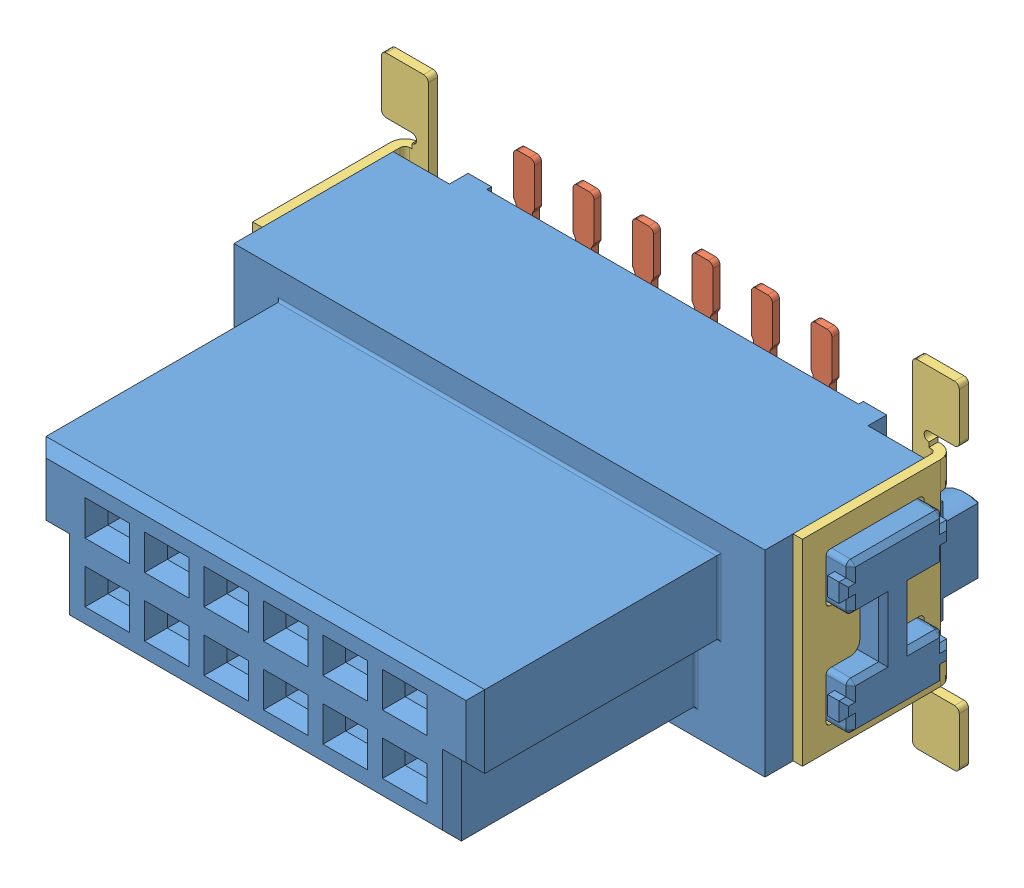
SolidWorks assembly m55-6011242_asm, configuration Default. Lengths in mm.
Overall size (12.7 7.2 9.8).
17 component instances, 4 part files, 0 mates.
Components (placement in the parent):
- m55-6011242_asm.stp-1: m55-6011242_asm.stp [Default] at origin size (12.7 7.2 11.05)
  - M55-60112_MOULD.stp-1: M55-60112_MOULD.stp [Default] at origin size (12.7 4.2 9.8)
  - M55-601_CONTACT.stp-1: M55-601_CONTACT.stp [Default] at (-3.175 0.635 0.4) x (1 0 0) z (0 -1 0) size (1.05 8.04 3.02)
  - M55-601_CONTACT.stp-2: M55-601_CONTACT.stp [Default] at (-1.905 0.635 0.4) x (1 0 0) z (0 -1 0) size (1.05 8.04 3.02)
  - M55-601_CONTACT.stp-3: M55-601_CONTACT.stp [Default] at (-0.635 0.635 0.4) x (1 0 0) z (0 -1 0) size (1.05 8.04 3.02)
  - M55-601_CONTACT.stp-4: M55-601_CONTACT.stp [Default] at (0.635 0.635 0.4) x (1 0 0) z (0 -1 0) size (1.05 8.04 3.02)
  - M55-601_CONTACT.stp-5: M55-601_CONTACT.stp [Default] at (1.905 0.635 0.4) x (1 0 0) z (0 -1 0) size (1.05 8.04 3.02)
  - M55-601_CONTACT.stp-6: M55-601_CONTACT.stp [Default] at (3.175 0.635 0.4) x (1 0 0) z (0 -1 0) size (1.05 8.04 3.02)
  - M55-601_CONTACT.stp-7: M55-601_CONTACT.stp [Default] at (-3.175 -0.635 0.4) x (-1 0 0) z (0 1 0) size (1.05 8.04 3.02)
  - M55-601_CONTACT.stp-8: M55-601_CONTACT.stp [Default] at (-1.905 -0.635 0.4) x (-1 0 0) z (0 1 0) size (1.05 8.04 3.02)
  - M55-601_CONTACT.stp-9: M55-601_CONTACT.stp [Default] at (-0.635 -0.635 0.4) x (-1 0 0) z (0 1 0) size (1.05 8.04 3.02)
  - M55-601_CONTACT.stp-10: M55-601_CONTACT.stp [Default] at (0.635 -0.635 0.4) x (-1 0 0) z (0 1 0) size (1.05 8.04 3.02)
  - M55-601_CONTACT.stp-11: M55-601_CONTACT.stp [Default] at (1.905 -0.635 0.4) x (-1 0 0) z (0 1 0) size (1.05 8.04 3.02)
  - M55-601_CONTACT.stp-12: M55-601_CONTACT.stp [Default] at (3.175 -0.635 0.4) x (-1 0 0) z (0 1 0) size (1.05 8.04 3.02)
  - M55-700_STRAP.stp-1: M55-700_STRAP.stp [Default] at (5.67 0 -0.05) x (-1 0 0) z (0 1 0) size (1 3.25 7.2)
  - M55-700_STRAP.stp-2: M55-700_STRAP.stp [Default] at (-5.67 0 -0.05) x (1 0 0) z (0 -1 0) size (1 3.25 7.2)
  - M55-600_CAP.stp-1: M55-600_CAP.stp [Default] at (0 0 10.25) x (0 -1 0) z (-1 0 0) size (4.75 4.25 8) (hidden)
